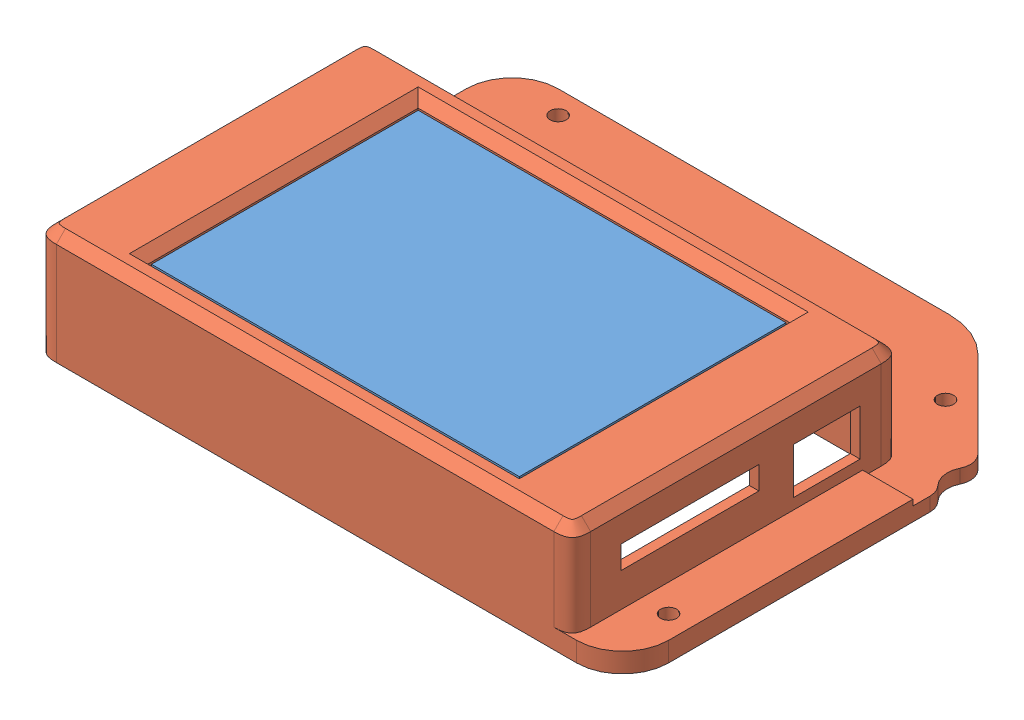
SolidWorks assembly SMW_MKS_TFT_ASMB, configuration Default. Lengths in mm.
Overall size (136.89 24.27 91.05).
3 component instances, 3 part files, 6 mates.
Components (placement in the parent):
- MKS_TTF_Cover-1: MKS_TTF_Cover [Default] at (38.4213 81.2289 107.5664) size (130.1 26.71 71.81) (hidden)
- MKS_TFT-1: MKS_TFT [Default] at (38.4213 77.2289 107.5664) x (1 0 0) z (0 1 0) size (110 65 6.6)
- Printed LCD Cover 2-1: Printed LCD Cover 2 [Default] at (38.4213 64.2289 107.5664) x (1 0 0) z (0 1 0) size (136.89 91.05 24.27)
Mates (geometry in assembly coordinates):
- Concentric1: concentric anti-aligned: cylinder of MKS_TTF_Cover-1 through (89.4213 65.2289 79.0664) axis (0 -1 0) radius 1.3; cylinder of MKS_TFT-1 through (89.4213 75.6289 79.0664) axis (0 1 0) radius 1.5
- Concentric2: concentric anti-aligned: cylinder of MKS_TTF_Cover-1 through (-12.5787 65.2289 136.0664) axis (0 -1 0) radius 1.3; cylinder of MKS_TFT-1 through (-12.5787 75.6289 136.0664) axis (0 1 0) radius 1.5
- Coincident1: coincident anti-aligned: plane of MKS_TTF_Cover-1 through (38.4213 77.2289 107.5664) normal (0 -1 0); plane of MKS_TFT-1 through (38.4213 77.2289 107.5664) normal (0 1 0)
- Concentric3: concentric aligned: cylinder of MKS_TFT-1 through (-12.5787 75.6289 136.0664) axis (0 1 0) radius 1.5; cylinder of Printed LCD Cover 2-1 through (-12.5787 77.2289 136.0664) axis (0 1 0) radius 1.3
- Concentric4: concentric aligned: cylinder of MKS_TFT-1 through (89.4213 75.6289 79.0664) axis (0 1 0) radius 1.5; cylinder of Printed LCD Cover 2-1 through (89.4213 77.2289 79.0664) axis (0 1 0) radius 1.3
- Coincident2: coincident anti-aligned: plane of MKS_TFT-1 through (38.4213 77.2289 107.5664) normal (0 1 0); plane of Printed LCD Cover 2-1 through (89.4213 77.2289 79.0664) normal (0 -1 0)
